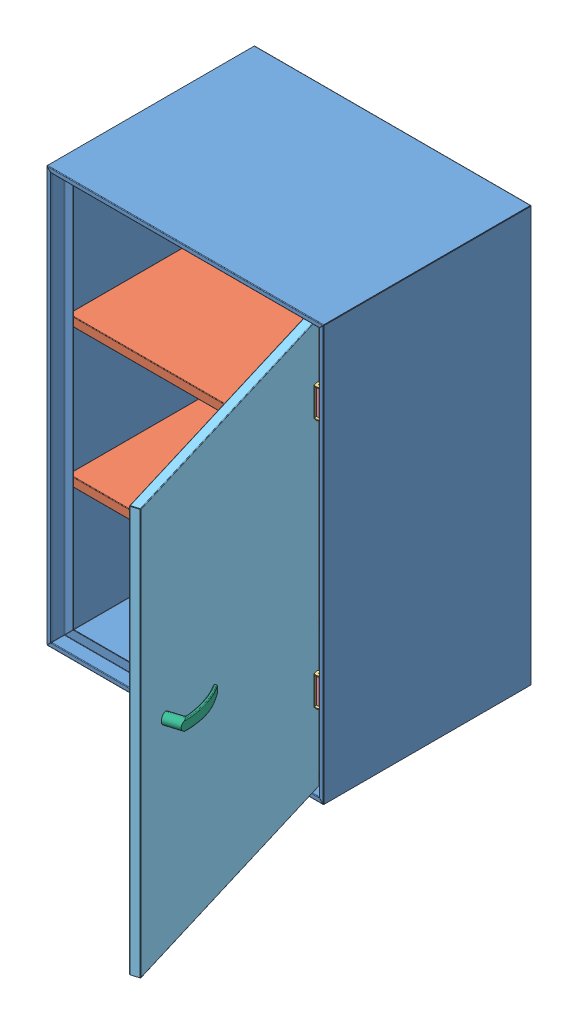
SolidWorks assembly Almirah, configuration Default. Lengths in mm.
Overall size (777.72 914.4 1004.54).
9 component instances, 6 part files, 19 mates.
Components (placement in the parent):
- 1. Mainframe-1: 1. Mainframe [Default] at (330.595 467.8668 485.8701) size (609.6 914.4 457.2)
- 2. Rack-1: 2. Rack [Default] at (330.795 619.0668 690.8701) x (1 0 0) z (0 -1 0) size (608 410 20)
- 2. Rack-2: 2. Rack [Default] at (330.795 313.6668 690.8701) x (1 0 0) z (0 -1 0) size (608 410 20)
- 4. Hinge part 1-2: 4. Hinge part 1 [Default] at (614.1359 733.0668 930.0011) x (-0.289568 0 -0.957158) z (0 -1 0) size (15 15.09 64)
- 5. Hinge part 2-3: 5. Hinge part 2 [Default] at (625.395 793.0668 911.0701) x (-1 0 0) z (0 -1 0) size (32.07 21.97 60)
- 4. Hinge part 1-3: 4. Hinge part 1 [Default] at (614.1359 183.0668 930.0011) x (-0.289568 0 -0.957158) z (0 -1 0) size (15 15.09 64)
- 5. Hinge part 2-4: 5. Hinge part 2 [Default] at (625.395 243.0668 911.0701) x (-1 0 0) z (0 -1 0) size (32.07 21.97 60)
- 3. Door-2: 3. Door [Default] at (688.587 467.8668 1202.3089) x (0 1 0) z (0.289568 0 0.957158) size (894.41 20.01 589)
- 6. Handle-1: 6. Handle [Default] at (751.4183 467.8668 1407.924) x (0.004546 -0.999877 0.015026) z (-0.957158 0 0.289568) size (40.23 120.12 66.87)
Mates (geometry in assembly coordinates):
- Coincident1: coincident anti-aligned: plane of 1. Mainframe-1 through (634.795 467.8668 485.8701) normal (-1 0 0); plane of 2. Rack-1 through (634.795 619.0668 690.8701) normal (1 0 0)
- Coincident2: coincident anti-aligned: plane of 1. Mainframe-1 through (330.595 467.8668 485.8701) normal (0 0 1); plane of 2. Rack-1 through (330.795 619.0668 485.8701) normal (0 0 -1)
- Distance1: distance = 304.8 mm anti-aligned: plane of 1. Mainframe-1 through (330.595 924.4668 485.8701) normal (0 -1 0); plane of 2. Rack-1 through (330.795 619.6668 690.8701) normal (0 1 0)
- Coincident4: coincident anti-aligned: plane of 1. Mainframe-1 through (330.595 467.8668 485.8701) normal (0 0 1); plane of 2. Rack-2 through (330.795 313.6668 485.8701) normal (0 0 -1)
- Coincident5: coincident anti-aligned: plane of 1. Mainframe-1 through (634.795 467.8668 485.8701) normal (-1 0 0); plane of 2. Rack-2 through (634.795 313.6668 690.8701) normal (1 0 0)
- Distance2: distance = 304.8 mm anti-aligned: plane of 2. Rack-2 through (330.795 314.2668 690.8701) normal (0 1 0); plane of 2. Rack-1 through (330.795 619.0668 690.8701) normal (0 -1 0)
- Concentric3: concentric aligned: cylinder of 4. Hinge part 1-2 through (614.1359 795.0668 930.0011) axis (0 -1 0) radius 1.5; cylinder of 5. Hinge part 2-3 through (614.1359 793.0668 930.0011) axis (0 -1 0) radius 2
- Width5: width anti-aligned: plane of 5. Hinge part 2-3 through (595.5396 793.0668 927.5285) normal (0 1 0); plane of 5. Hinge part 2-3 through (595.5396 733.0668 918.7539) normal (0 -1 0); plane of 4. Hinge part 1-2 through (614.1359 731.0668 930.0011) normal (0 -1 0); plane of 4. Hinge part 1-2 through (608.3188 795.0668 936.9848) normal (0 1 0)
- Coincident13: coincident anti-aligned: plane of 1. Mainframe-1 through (625.395 467.8668 485.8701) normal (-1 0 0); plane of 5. Hinge part 2-3 through (625.395 733.0668 913.0701) normal (1 0 0)
- Coincident14: coincident aligned: plane of 1. Mainframe-1 through (330.595 467.8668 913.0701) normal (0 0 1); plane of 5. Hinge part 2-3 through (625.395 733.0668 913.0701) normal (0 0 1)
- Distance5: distance = 120 mm anti-aligned: plane of 4. Hinge part 1-2 through (608.3188 795.0668 936.9848) normal (0 1 0); plane of 1. Mainframe-1 through (330.595 915.0668 485.8701) normal (0 -1 0)
- Coincident16: coincident aligned: plane of 4. Hinge part 1-2 through (606.8709 733.0668 932.199) normal (-0.957158 0 0.289568); plane of 3. Door-2 through (688.587 467.8668 1202.3089) normal (-0.957158 0 0.289568)
- Coincident17: coincident aligned: plane of 4. Hinge part 1-3 through (606.8709 183.0668 932.199) normal (-0.957158 0 0.289568); plane of 3. Door-2 through (688.587 467.8668 1202.3089) normal (-0.957158 0 0.289568)
- Distance6: distance = 16 mm aligned: plane of 4. Hinge part 1-2 through (608.3188 731.0668 936.9848) normal (0.289568 0 0.957158); plane of 3. Door-2 through (597.871 467.8668 923.4294) normal (0.289568 0 0.957158)
- Width6: width aligned: plane of 1. Mainframe-1 through (330.595 925.0668 485.8701) normal (0 1 0); plane of 1. Mainframe-1 through (330.595 10.6668 485.8701) normal (0 -1 0); plane of 3. Door-2 through (688.587 915.0668 1202.3089) normal (0 1 0); plane of 3. Door-2 through (688.587 20.6668 1202.3089) normal (0 -1 0)
- LimitAngle3: limit planar angle = 1.864572 rad aligned: plane of 1. Mainframe-1 through (330.595 467.8668 942.4701) normal (0 0 1); plane of 3. Door-2 through (689.1613 467.8668 1202.1351) normal (0.957158 0 -0.289568)
- Concentric4: concentric aligned: cylinder of 3. Door-2 through (750.844 467.8668 1408.0977) axis (0.957158 0 -0.289568) radius 8; cylinder of 6. Handle-1 through (736.1038 467.8668 1412.5571) axis (0.957158 0 -0.289568) radius 8
- Coincident19: coincident anti-aligned: plane of 3. Door-2 through (689.1613 467.8668 1202.1351) normal (0.957158 0 -0.289568); plane of 6. Handle-1 through (751.4183 467.8668 1407.924) normal (-0.957158 0 0.289568)
- Lock1: lock: unknown of 3. Door-2; unknown of 6. Handle-1
